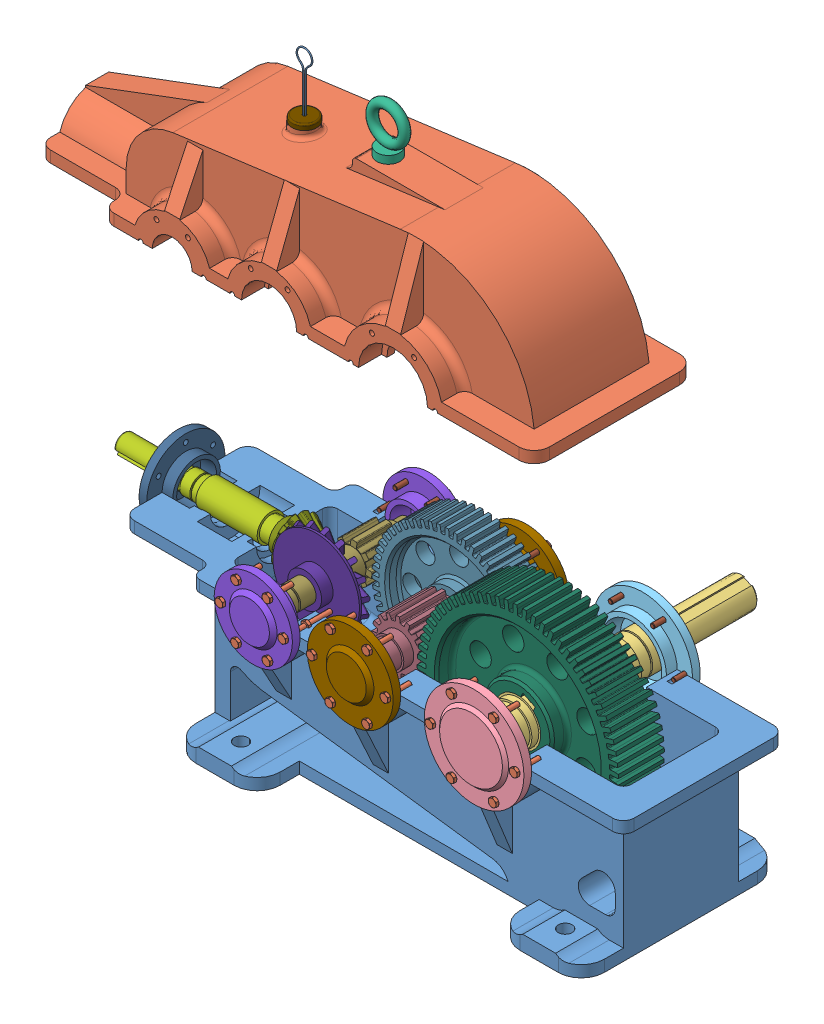
SolidWorks assembly Montagem redutor 4 eixos, configuration Valor predeterminado. Lengths in mm.
Overall size (757.14 825.89 416.81).
61 component instances, 20 part files, 122 mates.
Components (placement in the parent):
- corpo inferior-1: corpo inferior [Valor predeterminado] at (-28.8021 103.2767 0) size (676 185 260)
- corpo superior-1: corpo superior [Valor predeterminado] at (-68.7916 522.3028 75.8076) size (675.27 156.38 210)
- Peça 34-1: Peça 34 [Valor predeterminado] at (125.2979 103.2767 -709.2316) x (0 0 -1) z (0.906664 -0.421854 0) size (325 65 65)
- Peça 44-1: Peça 44 [Valor predeterminado] at (125.2979 103.2767 115) x (1 0 0) z (0 1 0) size (130 28 130)
- Peça 36-1: Peça 36 [Valor predeterminado] at (125.2979 103.2767 -115) x (1 0 0) z (0 -1 0) size (130 28 130)
- peça 3 - anilha-1: peça 3 - anilha [Valor predeterminado] at (-25.7916 713.0575 75.8076) size (54 83 30)
- Peça 19-1: Peça 19 [Valor predeterminado] at (-320.1919 103.2767 0) x (1 0 0) z (0 -0.917943 -0.396712) size (239.28 36 36)
- Peça 25-1: Peça 25 [Valor predeterminado] at (-162.8021 103.2767 -115) x (1 0 0) z (0 -1 0) size (102 32 102)
- Peça 29-1: Peça 29 [Valor predeterminado] at (-36.4021 103.2767 -115) x (1 0 0) z (0 -1 0) size (112 28 112)
- Peça 25-2: Peça 25 [Valor predeterminado] at (-162.8021 103.2767 115) x (1 0 0) z (0 1 0) size (102 32 102)
- Peça 29-2: Peça 29 [Valor predeterminado] at (-36.4021 103.2767 115) x (1 0 0) z (0 1 0) size (112 28 112)
- Peça 14-1: Peça 14 [Valor predeterminado] at (-375.8021 103.2767 0) x (0 -1 0) z (0 0 1) size (102 29 102)
- hex bolt gradeb_iso-2: hex bolt gradeb_iso [ISO 4015 - M6 x 25 x 18-N] at (-183.3016 67.7688 -119) x (0 0 1) z (-1 0 0) size (29 11.55 10)
- hex bolt gradeb_iso-3: hex bolt gradeb_iso [ISO 4015 - M6 x 25 x 18-N] at (-203.8021 103.2767 -119) x (0 0 1) z (-1 0 0) size (29 11.55 10)
- hex bolt gradeb_iso-6: hex bolt gradeb_iso [ISO 4015 - M6 x 25 x 18-N] at (-142.3006 138.7846 -119) x (0 0 1) z (-1 0 0) size (29 11.55 10)
- hex bolt gradeb_iso-7: hex bolt gradeb_iso [ISO 4015 - M6 x 25 x 18-N] at (-183.3016 138.7846 -119) x (0 0 1) z (-1 0 0) size (29 11.55 10)
- hex bolt gradeb_iso-8: hex bolt gradeb_iso [ISO 4015 - M6 x 25 x 18-N] at (-60.4016 144.8468 -119) x (0 0 1) z (-1 0 0) size (29 11.55 10)
- hex bolt gradeb_iso-9: hex bolt gradeb_iso [ISO 4015 - M6 x 25 x 18-N] at (-84.4021 103.2767 -119) x (0 0 1) z (-1 0 0) size (29 11.55 10)
- hex bolt gradeb_iso-10: hex bolt gradeb_iso [ISO 4015 - M6 x 25 x 18-N] at (-60.4016 61.7066 -119) x (0 0 1) z (-1 0 0) size (29 11.55 10)
- hex bolt gradeb_iso-11: hex bolt gradeb_iso [ISO 4015 - M6 x 25 x 18-N] at (-12.4006 61.7066 -119) x (0 0 1) z (-1 0 0) size (29 11.55 10)
- hex bolt gradeb_iso-12: hex bolt gradeb_iso [ISO 4015 - M6 x 25 x 18-N] at (11.5999 103.2767 -119) x (0 0 1) z (-1 0 0) size (29 11.55 10)
- hex bolt gradeb_iso-13: hex bolt gradeb_iso [ISO 4015 - M6 x 25 x 18-N] at (-12.4006 144.8468 -119) x (0 0 1) z (-1 0 0) size (29 11.55 10)
- hex bolt gradeb_iso-14: hex bolt gradeb_iso [ISO 4015 - M6 x 25 x 18-N] at (70.2979 103.2767 -119) x (0 0 1) z (-1 0 0) size (29 11.55 10)
- hex bolt gradeb_iso-15: hex bolt gradeb_iso [ISO 4015 - M6 x 25 x 18-N] at (97.7984 150.909 -119) x (0 0 1) z (-1 0 0) size (29 11.55 10)
- hex bolt gradeb_iso-16: hex bolt gradeb_iso [ISO 4015 - M6 x 25 x 18-N] at (97.7984 55.6445 -119) x (0 0 1) z (-1 0 0) size (29 11.55 10)
- hex bolt gradeb_iso-17: hex bolt gradeb_iso [ISO 4015 - M6 x 25 x 18-N] at (125.2979 103.2767 -109) x (0 0 1) z (-1 0 0) size (29 11.55 10)
- hex bolt gradeb_iso-18: hex bolt gradeb_iso [ISO 4015 - M6 x 25 x 18-N] at (180.2999 103.2767 -119) x (0 0 1) z (-1 0 0) size (29 11.55 10)
- hex bolt gradeb_iso-19: hex bolt gradeb_iso [ISO 4015 - M6 x 25 x 18-N] at (125.2979 103.2767 -109) x (0 0 1) z (-1 0 0) size (29 11.55 10)
- hex bolt gradeb_iso-20: hex bolt gradeb_iso [ISO 4015 - M6 x 25 x 18-N] at (152.7994 55.6445 -119) x (0 0 1) z (-1 0 0) size (29 11.55 10)
- hex bolt gradeb_iso-21: hex bolt gradeb_iso [ISO 4015 - M6 x 25 x 18-N] at (152.7994 150.909 -119) x (0 0 1) z (-1 0 0) size (29 11.55 10)
- hex bolt gradeb_iso-22: hex bolt gradeb_iso [ISO 4015 - M6 x 25 x 18-N] at (-121.8001 103.2767 -119) x (0 0 1) z (-1 0 0) size (29 11.55 10)
- hex bolt gradeb_iso-23: hex bolt gradeb_iso [ISO 4015 - M6 x 25 x 18-N] at (-142.3006 67.7688 -119) x (0 0 1) z (-1 0 0) size (29 11.55 10)
- Peça 24-1: Peça 24 [Valor predeterminado] at (-162.8021 103.2767 -27.9422) x (0 0 -1) z (0.995789 -0.091673 0) size (172 51.48 51.48)
- Peça 28-1: Peça 28 [Valor predeterminado] at (-36.4021 103.2767 -80.4292) x (0 0 -1) z (-0.999605 -0.028103 0) size (189 69.85 69.85)
- Peça 26-1: Peça 26 [Valor predeterminado] at (-36.4021 103.2767 -36.5) x (-0.999605 -0.028103 0) z (0 0 1) size (200.95 200.95 45)
- Peça 42-1: Peça 42 [Valor predeterminado] at (125.2979 103.2767 28) x (-0.906664 0.421854 0) z (0 0 1) size (262.46 262.46 60)
- Peça 21-1: Peça 21 [Valor predeterminado] at (-163.1706 103.2767 0) x (1 0 0) z (0 -0.917943 -0.396712) size (38.86 64.44 64.44)
- Peça 22-1: Peça 22 [Valor predeterminado] at (-162.8021 103.2767 20.6607) x (0 0 -1) z (0.719152 -0.694853 0) size (43 117.86 116.57)
- vareta de oleo-3: vareta de oleo [Valor predeterminado] at (-137.3021 649.47 75.8076) x (0 -1 0) z (0 0 1) size (295.59 32 32)
  - Peça 2-1: Peça 2 [Valor predeterminado] at (28.8886 2.1661 0) size (27 32 32)
  - Peça 1 - vareta do oleo-1: Peça 1 - vareta do oleo [Valor predeterminado] at (-84 2.1661 0) size (295.59 21.4 1.4)
- hex bolt gradeab_iso-1: hex bolt gradeab_iso [ISO 4014 - M6 x 30 x 18-N] at (125.2979 103.2767 119) x (0 0 -1) z (1 0 0) size (34 11.55 10)
- hex bolt gradeab_iso-2: hex bolt gradeab_iso [ISO 4014 - M6 x 30 x 18-N] at (-142.3006 138.7846 119) x (0 0 -1) z (1 0 0) size (34 11.55 10)
- hex bolt gradeab_iso-3: hex bolt gradeab_iso [ISO 4014 - M6 x 30 x 18-N] at (-183.3016 138.7846 119) x (0 0 -1) z (1 0 0) size (34 11.55 10)
- hex bolt gradeab_iso-5: hex bolt gradeab_iso [ISO 4014 - M6 x 30 x 18-N] at (-183.3016 67.7688 119) x (0 0 -1) z (1 0 0) size (34 11.55 10)
- hex bolt gradeab_iso-6: hex bolt gradeab_iso [ISO 4014 - M6 x 30 x 18-N] at (-142.3006 67.7688 119) x (0 0 -1) z (1 0 0) size (34 11.55 10)
- hex bolt gradeab_iso-7: hex bolt gradeab_iso [ISO 4014 - M6 x 30 x 18-N] at (-121.8021 103.2767 89) x (0 0 -1) z (1 0 0) size (34 11.55 10)
- hex bolt gradeab_iso-8: hex bolt gradeab_iso [ISO 4014 - M6 x 30 x 18-N] at (-121.8001 103.2767 119) x (0 0 -1) z (1 0 0) size (34 11.55 10)
- hex bolt gradeab_iso-9: hex bolt gradeab_iso [ISO 4014 - M6 x 30 x 18-N] at (-84.4021 103.2767 119) x (0 0 -1) z (1 0 0) size (34 11.55 10)
- hex bolt gradeab_iso-10: hex bolt gradeab_iso [ISO 4014 - M6 x 30 x 18-N] at (-60.4016 61.7066 119) x (0 0 -1) z (1 0 0) size (34 11.55 10)
- hex bolt gradeab_iso-11: hex bolt gradeab_iso [ISO 4014 - M6 x 30 x 18-N] at (-12.4006 61.7066 119) x (0 0 -1) z (1 0 0) size (34 11.55 10)
- hex bolt gradeab_iso-12: hex bolt gradeab_iso [ISO 4014 - M6 x 30 x 18-N] at (11.5999 103.2767 119) x (0 0 -1) z (1 0 0) size (34 11.55 10)
- hex bolt gradeab_iso-13: hex bolt gradeab_iso [ISO 4014 - M6 x 30 x 18-N] at (-12.4006 144.8468 119) x (0 0 -1) z (1 0 0) size (34 11.55 10)
- hex bolt gradeab_iso-14: hex bolt gradeab_iso [ISO 4014 - M6 x 30 x 18-N] at (-60.4016 144.8468 119) x (0 0 -1) z (1 0 0) size (34 11.55 10)
- hex bolt gradeab_iso-15: hex bolt gradeab_iso [ISO 4014 - M6 x 30 x 18-N] at (-203.8021 103.2767 119) x (0 0 -1) z (1 0 0) size (34 11.55 10)
- hex bolt gradeab_iso-16: hex bolt gradeab_iso [ISO 4014 - M6 x 30 x 18-N] at (70.2979 103.2767 119) x (0 0 -1) z (1 0 0) size (34 11.55 10)
- hex bolt gradeab_iso-17: hex bolt gradeab_iso [ISO 4014 - M6 x 30 x 18-N] at (97.7984 150.909 119) x (0 0 -1) z (1 0 0) size (34 11.55 10)
- hex bolt gradeab_iso-18: hex bolt gradeab_iso [ISO 4014 - M6 x 30 x 18-N] at (152.7994 150.909 119) x (0 0 -1) z (1 0 0) size (34 11.55 10)
- hex bolt gradeab_iso-19: hex bolt gradeab_iso [ISO 4014 - M6 x 30 x 18-N] at (180.2999 103.2767 119) x (0 0 -1) z (1 0 0) size (34 11.55 10)
- hex bolt gradeab_iso-20: hex bolt gradeab_iso [ISO 4014 - M6 x 30 x 18-N] at (152.7994 55.6445 119) x (0 0 -1) z (1 0 0) size (34 11.55 10)
- hex bolt gradeab_iso-21: hex bolt gradeab_iso [ISO 4014 - M6 x 30 x 18-N] at (97.7984 55.6445 119) x (0 0 -1) z (1 0 0) size (34 11.55 10)
Mates (geometry in assembly coordinates):
- Concêntrico1: concentric aligned: cylinder of corpo inferior-1 through (125.2979 103.2767 -130.001) axis (0 0 1) radius 45; cylinder of corpo inferior-1 through (125.2979 103.2767 75) axis (0 0 1) radius 45
- Concêntrico2: concentric anti-aligned: cylinder of corpo inferior-1 through (-365.8021 103.2767 0) axis (-1 0 0) radius 31; cylinder of corpo inferior-1 through (-229.8021 103.2767 0) axis (1 0 0) radius 31
- Concêntrico3: concentric aligned: cylinder of corpo inferior-1 through (125.2979 103.2767 -130.001) axis (0 0 1) radius 45; cylinder of Peça 34-1 through (125.2979 103.2767 -658.78) axis (0 0 1) radius 30
- Concêntrico4: concentric anti-aligned: cylinder of corpo inferior-1 through (125.2979 103.2767 -130.001) axis (0 0 1) radius 45; cylinder of Peça 44-1 through (125.2979 103.2767 31.1749) axis (0 0 -1) radius 45
- Coincidente1: coincident anti-aligned: plane of corpo inferior-1 through (-162.8021 103.2767 105) normal (0 0 1); plane of Peça 44-1 through (60.2979 103.2767 105) normal (0 0 -1)
- Concêntrico5: concentric anti-aligned: cylinder of Peça 34-1 through (125.2979 103.2767 -658.78) axis (0 0 1) radius 22.5; cone of Peça 36-1 through (125.2979 103.2767 -110) axis (0 0 -1)
- Concêntrico6: concentric aligned: cylinder of corpo inferior-1 through (125.2979 103.2767 -130.001) axis (0 0 1) radius 45; cylinder of Peça 36-1 through (125.2979 103.2767 -31.1749) axis (0 0 1) radius 45
- Coincidente2: coincident anti-aligned: plane of corpo inferior-1 through (-162.8021 103.2767 -105) normal (0 0 -1); plane of Peça 36-1 through (60.2979 103.2767 -105) normal (0 0 1)
- Distância1: distance = 2 mm anti-aligned: plane of Peça 34-1 through (135.8442 125.9433 67) normal (0 0 1); plane of corpo inferior-1 through (-182.8021 58.2767 65) normal (0 0 -1)
- Coincidente6: coincident anti-aligned: plane of corpo superior-1 through (73.1477 677.0575 100.8076) normal (0 1 0); plane of peça 3 - anilha-1 through (-25.7916 677.0575 75.8076) normal (0 -1 0)
- Concêntrico10: concentric aligned: cylinder of corpo superior-1 through (-25.7916 522.3028 75.8076) axis (0 1 0) radius 6.25; cylinder of peça 3 - anilha-1 through (-25.7916 657.0575 75.8076) axis (0 1 0) radius 6
- Concêntrico11: concentric aligned: cylinder of corpo inferior-1 through (-365.8021 103.2767 0) axis (-1 0 0) radius 31; cylinder of Peça 19-1 through (-474.027 103.2767 0) axis (-1 0 0) radius 18
- Coincidente8: coincident aligned: plane of corpo inferior-1 through (-254.8021 103.2767 -24) normal (1 0 0); plane of Peça 19-1 through (-254.8021 96.1359 16.523) normal (1 0 0)
- Coincidente10: coincident anti-aligned: plane of corpo inferior-1 through (-162.8021 103.2767 105) normal (0 0 1); plane of Peça 25-2 through (-213.8021 103.2767 105) normal (0 0 -1)
- Concêntrico13: concentric aligned: cylinder of corpo inferior-1 through (-162.8021 103.2767 -130.001) axis (0 0 1) radius 31; cylinder of Peça 25-1 through (-162.8021 103.2767 -31.1749) axis (0 0 1) radius 31
- Coincidente11: coincident anti-aligned: plane of corpo inferior-1 through (-162.8021 103.2767 -105) normal (0 0 -1); plane of Peça 25-1 through (-213.8021 103.2767 -105) normal (0 0 1)
- Concêntrico14: concentric anti-aligned: cylinder of corpo inferior-1 through (-36.4021 103.2767 -130.001) axis (0 0 1) radius 36; cylinder of Peça 29-2 through (-36.4021 103.2767 31.1749) axis (0 0 -1) radius 36
- Coincidente12: coincident anti-aligned: plane of corpo inferior-1 through (-162.8021 103.2767 105) normal (0 0 1); plane of Peça 29-2 through (-92.4021 103.2767 105) normal (0 0 -1)
- Concêntrico15: concentric aligned: cylinder of corpo inferior-1 through (-36.4021 103.2767 -130.001) axis (0 0 1) radius 36; cylinder of Peça 29-1 through (-36.4021 103.2767 -31.1749) axis (0 0 1) radius 36
- Coincidente13: coincident anti-aligned: plane of corpo inferior-1 through (-162.8021 103.2767 -105) normal (0 0 -1); plane of Peça 29-1 through (-92.4021 103.2767 -105) normal (0 0 1)
- Concêntrico16: concentric anti-aligned: cylinder of corpo inferior-1 through (-365.8021 103.2767 0) axis (-1 0 0) radius 31; cylinder of Peça 14-1 through (-291.9771 103.2767 0) axis (1 0 0) radius 31
- Coincidente14: coincident anti-aligned: plane of corpo inferior-1 through (-365.8021 103.2767 0) normal (-1 0 0); plane of Peça 14-1 through (-365.8021 154.2767 0) normal (1 0 0)
- Concêntrico171: concentric anti-aligned: cylinder of Peça 25-1 through (-183.3016 67.7688 -120) axis (0 0 1) radius 3.175; cylinder of hex bolt gradeb_iso-2 through (-183.3016 67.7688 -119) axis (0 0 -1) radius 3
- Coincidente151: coincident anti-aligned: plane of Peça 25-1 through (-213.8021 103.2767 -115) normal (0 0 -1); plane of hex bolt gradeb_iso-2 through (-183.3016 73.5423 -115) normal (0 0 1)
- Concêntrico18: concentric anti-aligned: cylinder of Peça 25-1 through (-203.8021 103.2767 -120) axis (0 0 1) radius 3.175; cylinder of hex bolt gradeb_iso-3 through (-203.8021 103.2767 -119) axis (0 0 -1) radius 3
- Coincidente16: coincident anti-aligned: plane of Peça 25-1 through (-213.8021 103.2767 -115) normal (0 0 -1); plane of hex bolt gradeb_iso-3 through (-203.8021 109.0502 -115) normal (0 0 1)
- Concêntrico21: concentric anti-aligned: cylinder of Peça 25-1 through (-142.3006 138.7846 -120) axis (0 0 1) radius 3.175; cylinder of hex bolt gradeb_iso-6 through (-142.3006 138.7846 -119) axis (0 0 -1) radius 3
- Coincidente17: coincident anti-aligned: plane of Peça 25-1 through (-213.8021 103.2767 -115) normal (0 0 -1); plane of hex bolt gradeb_iso-6 through (-142.3006 144.5581 -115) normal (0 0 1)
- Concêntrico22: concentric anti-aligned: cylinder of Peça 25-1 through (-183.3016 138.7846 -120) axis (0 0 1) radius 3.175; cylinder of hex bolt gradeb_iso-7 through (-183.3016 138.7846 -119) axis (0 0 -1) radius 3
- Coincidente18: coincident anti-aligned: plane of Peça 25-1 through (-213.8021 103.2767 -115) normal (0 0 -1); plane of hex bolt gradeb_iso-7 through (-183.3016 144.5581 -115) normal (0 0 1)
- Concêntrico23: concentric anti-aligned: cylinder of Peça 29-1 through (-60.4016 144.8468 -120) axis (0 0 1) radius 3.175; cylinder of hex bolt gradeb_iso-8 through (-60.4016 144.8468 -119) axis (0 0 -1) radius 3
- Coincidente19: coincident anti-aligned: plane of Peça 29-1 through (-92.4021 103.2767 -115) normal (0 0 -1); plane of hex bolt gradeb_iso-8 through (-60.4016 150.6203 -115) normal (0 0 1)
- Concêntrico24: concentric anti-aligned: cylinder of Peça 29-1 through (-84.4021 103.2767 -120) axis (0 0 1) radius 3.175; cylinder of hex bolt gradeb_iso-9 through (-84.4021 103.2767 -119) axis (0 0 -1) radius 3
- Coincidente20: coincident anti-aligned: plane of Peça 29-1 through (-92.4021 103.2767 -115) normal (0 0 -1); plane of hex bolt gradeb_iso-9 through (-84.4021 109.0502 -115) normal (0 0 1)
- Concêntrico25: concentric anti-aligned: cylinder of Peça 29-1 through (-60.4016 61.7066 -120) axis (0 0 1) radius 3.175; cylinder of hex bolt gradeb_iso-10 through (-60.4016 61.7066 -119) axis (0 0 -1) radius 3
- Coincidente21: coincident anti-aligned: plane of Peça 29-1 through (-92.4021 103.2767 -115) normal (0 0 -1); plane of hex bolt gradeb_iso-10 through (-60.4016 67.4802 -115) normal (0 0 1)
- Concêntrico26: concentric anti-aligned: cylinder of Peça 29-1 through (-12.4006 61.7066 -120) axis (0 0 1) radius 3.175; cylinder of hex bolt gradeb_iso-11 through (-12.4006 61.7066 -119) axis (0 0 -1) radius 3
- Coincidente22: coincident anti-aligned: plane of Peça 29-1 through (-92.4021 103.2767 -115) normal (0 0 -1); plane of hex bolt gradeb_iso-11 through (-12.4006 67.4802 -115) normal (0 0 1)
- Concêntrico27: concentric anti-aligned: cylinder of Peça 29-1 through (11.5999 103.2767 -120) axis (0 0 1) radius 3.175; cylinder of hex bolt gradeb_iso-12 through (11.5999 103.2767 -119) axis (0 0 -1) radius 3
- Coincidente23: coincident anti-aligned: plane of Peça 29-1 through (-92.4021 103.2767 -115) normal (0 0 -1); plane of hex bolt gradeb_iso-12 through (11.5999 109.0502 -115) normal (0 0 1)
- Concêntrico28: concentric anti-aligned: cylinder of Peça 29-1 through (-12.4006 144.8468 -120) axis (0 0 1) radius 3.175; cylinder of hex bolt gradeb_iso-13 through (-12.4006 144.8468 -119) axis (0 0 -1) radius 3
- Coincidente24: coincident anti-aligned: plane of Peça 29-1 through (-92.4021 103.2767 -115) normal (0 0 -1); plane of hex bolt gradeb_iso-13 through (-12.4006 150.6203 -115) normal (0 0 1)
- Concêntrico29: concentric anti-aligned: cylinder of Peça 36-1 through (70.2979 103.2767 -119) axis (0 0 1) radius 3.175; cylinder of hex bolt gradeb_iso-14 through (70.2979 103.2767 -119) axis (0 0 -1) radius 3
- Coincidente25: coincident anti-aligned: plane of Peça 36-1 through (60.2979 103.2767 -115) normal (0 0 -1); plane of hex bolt gradeb_iso-14 through (70.2979 109.0502 -115) normal (0 0 1)
- Concêntrico30: concentric anti-aligned: cylinder of Peça 36-1 through (97.7984 150.909 -119) axis (0 0 1) radius 3.175; cylinder of hex bolt gradeb_iso-15 through (97.7984 150.909 -119) axis (0 0 -1) radius 3
- Coincidente26: coincident anti-aligned: plane of Peça 36-1 through (60.2979 103.2767 -115) normal (0 0 -1); plane of hex bolt gradeb_iso-15 through (97.7984 156.6825 -115) normal (0 0 1)
- Concêntrico31: concentric anti-aligned: cylinder of Peça 36-1 through (97.7984 55.6445 -119) axis (0 0 1) radius 3.175; cylinder of hex bolt gradeb_iso-16 through (97.7984 55.6445 -119) axis (0 0 -1) radius 3
- Coincidente27: coincident anti-aligned: plane of Peça 36-1 through (60.2979 103.2767 -115) normal (0 0 -1); plane of hex bolt gradeb_iso-16 through (97.7984 61.418 -115) normal (0 0 1)
- Concêntrico321: concentric aligned: cylinder of corpo inferior-1 through (125.2979 103.2767 105) axis (0 0 -1) radius 65; cylinder of hex bolt gradeb_iso-17 through (125.2979 103.2767 -109) axis (0 0 -1) radius 3
- Coincidente281: coincident anti-aligned: plane of corpo inferior-1 through (-162.8021 103.2767 -105) normal (0 0 -1); plane of hex bolt gradeb_iso-17 through (125.2979 109.0502 -105) normal (0 0 1)
- Concêntrico33: concentric anti-aligned: cylinder of Peça 36-1 through (180.2999 103.2767 -119) axis (0 0 1) radius 3.175; cylinder of hex bolt gradeb_iso-18 through (180.2999 103.2767 -119) axis (0 0 -1) radius 3
- Coincidente29: coincident anti-aligned: plane of Peça 36-1 through (60.2979 103.2767 -115) normal (0 0 -1); plane of hex bolt gradeb_iso-18 through (180.2999 109.0502 -115) normal (0 0 1)
- Concêntrico341: concentric anti-aligned: cylinder of corpo inferior-1 through (125.2979 103.2767 -130.001) axis (0 0 1) radius 45; cylinder of hex bolt gradeb_iso-19 through (125.2979 103.2767 -109) axis (0 0 -1) radius 3
- Coincidente301: coincident anti-aligned: plane of corpo inferior-1 through (-162.8021 103.2767 -105) normal (0 0 -1); plane of hex bolt gradeb_iso-19 through (125.2979 109.0502 -105) normal (0 0 1)
- Concêntrico35: concentric anti-aligned: cylinder of Peça 36-1 through (152.7994 55.6445 -119) axis (0 0 1) radius 3.175; cylinder of hex bolt gradeb_iso-20 through (152.7994 55.6445 -119) axis (0 0 -1) radius 3
- Coincidente31: coincident anti-aligned: plane of Peça 36-1 through (60.2979 103.2767 -115) normal (0 0 -1); plane of hex bolt gradeb_iso-20 through (152.7994 61.418 -115) normal (0 0 1)
- Concêntrico36: concentric anti-aligned: cylinder of Peça 36-1 through (152.7994 150.909 -119) axis (0 0 1) radius 3.175; cylinder of hex bolt gradeb_iso-21 through (152.7994 150.909 -119) axis (0 0 -1) radius 3
- Coincidente32: coincident anti-aligned: plane of Peça 36-1 through (60.2979 103.2767 -115) normal (0 0 -1); plane of hex bolt gradeb_iso-21 through (152.7994 156.6825 -115) normal (0 0 1)
- Concêntrico37: concentric anti-aligned: cylinder of Peça 25-1 through (-121.8001 103.2767 -120) axis (0 0 1) radius 3.175; cylinder of hex bolt gradeb_iso-22 through (-121.8001 103.2767 -119) axis (0 0 -1) radius 3
- Coincidente33: coincident anti-aligned: plane of Peça 25-1 through (-213.8021 103.2767 -115) normal (0 0 -1); plane of hex bolt gradeb_iso-22 through (-121.8001 109.0502 -115) normal (0 0 1)
- Concêntrico38: concentric anti-aligned: cylinder of Peça 25-1 through (-142.3006 67.7688 -120) axis (0 0 1) radius 3.175; cylinder of hex bolt gradeb_iso-23 through (-142.3006 67.7688 -119) axis (0 0 -1) radius 3
- Coincidente34: coincident anti-aligned: plane of Peça 25-1 through (-213.8021 103.2767 -115) normal (0 0 -1); plane of hex bolt gradeb_iso-23 through (-142.3006 73.5423 -115) normal (0 0 1)
- Concêntrico342: concentric anti-aligned: cylinder of Peça 34-1 through (125.2979 103.2767 -658.78) axis (0 0 1) radius 30; cylinder of Peça 42-1 through (125.2979 103.2767 58) axis (0 0 -1) radius 30
- Coincidente303: coincident aligned: plane of Peça 34-1 through (127.2624 128.8334 6.5) normal (0.906664 -0.421854 0); plane of Peça 42-1 through (131.9028 138.8067 -2) normal (0.906664 -0.421854 0)
- Coincidente304: coincident aligned: plane of Peça 34-1 through (136.8988 128.21 58) normal (0 0 1); plane of Peça 42-1 through (125.2979 103.2767 58) normal (0 0 1)
- Concêntrico343: concentric aligned: cylinder of corpo inferior-1 through (-36.4021 103.2767 -130.001) axis (0 0 1) radius 36; cylinder of Peça 28-1 through (-36.4021 103.2767 105.5535) axis (0 0 1) radius 22.5
- Coincidente305: coincident anti-aligned: plane of corpo inferior-1 through (-182.8021 58.2767 65) normal (0 0 -1); plane of Peça 28-1 through (-35.9103 85.7836 65) normal (0 0 1)
- Concêntrico344: concentric anti-aligned: cylinder of Peça 28-1 through (-36.4021 103.2767 105.5535) axis (0 0 1) radius 22.5; cylinder of Peça 26-1 through (-36.4021 103.2767 -14) axis (0 0 -1) radius 22.5
- Paralelo1: parallel aligned: plane of Peça 28-1 through (-28.9131 85.9804 -52) normal (-0.999605 -0.028103 0); plane of Peça 26-1 through (-28.309 82.2827 -14) normal (-0.999605 -0.028103 0)
- Coincidente308: coincident anti-aligned: plane of Peça 28-1 through (-35.6996 78.2866 -14) normal (0 0 -1); plane of Peça 26-1 through (-36.4021 103.2767 -14) normal (0 0 1)
- Posic. engrenagem1: gear = 35 : 55 mm: cylinder of Peça 34-1 through (125.2979 103.2767 -658.78) axis (0 0 1) radius 27.5; cylinder of Peça 28-1 through (-36.4021 103.2767 105.5535) axis (0 0 1) radius 17.5
- Concêntrico345: concentric aligned: cylinder of corpo inferior-1 through (-162.8021 103.2767 -130.001) axis (0 0 1) radius 31; cylinder of Peça 24-1 through (-162.8021 103.2767 154.7526) axis (0 0 1) radius 15
- Distância2: distance = 6 mm anti-aligned: plane of corpo inferior-1 through (-182.8021 58.2767 -65) normal (0 0 1); plane of Peça 24-1 through (-161.1979 120.703 -71) normal (0 0 -1)
- Posic. engrenagem2: gear = 30 : 35 mm: cylinder of Peça 28-1 through (-36.4021 103.2767 105.5535) axis (0 0 1) radius 17.5; cylinder of Peça 24-1 through (-162.8021 103.2767 154.7526) axis (0 0 1) radius 15
- Concêntrico346: concentric aligned: cone of Peça 24-1 through (-162.8021 103.2767 5) axis (0 0 1); cone of Peça 22-1 through (-162.8021 103.2767 48) axis (0 0 1)
- Concêntrico347: concentric aligned: cylinder of Peça 19-1 through (-474.027 103.2767 0) axis (-1 0 0) radius 15; cylinder of Peça 21-1 through (-333.0795 103.2767 0) axis (-1 0 0) radius 14
- Coincidente309: coincident anti-aligned: circle of Peça 24-1; plane of Peça 22-1 through (-147.4122 119.2048 5) normal (0 0 -1)
- Posic. engrenagem3: gear = 36 : 36 mm: cylinder of Peça 24-1 through (-162.8021 103.2767 154.7526) axis (0 0 1) radius 18; cylinder of Peça 19-1 through (-474.027 103.2767 0) axis (-1 0 0) radius 18
- Paralelo2: parallel aligned: plane of Peça 19-1 through (-207.8021 103.3781 9.8483) normal (0 -0.917943 -0.396712); plane of Peça 21-1 through (-198.9411 100.3779 11.7489) normal (0 -0.917943 -0.396712)
- Coincidente311: coincident anti-aligned: plane of Peça 19-1 through (-237.8021 97.3261 13.7691) normal (1 0 0); plane of Peça 21-1 through (-237.8021 107.1134 -8.8775) normal (-1 0 0)
- Concêntrico348: concentric aligned: cylinder of corpo superior-1 through (-135.136 522.3028 75.8076) axis (0 1 0) radius 8.25; cylinder of vareta de oleo-3/Peça 2-1 through (-135.136 689.6639 75.8076) axis (0 1 0) radius 8
- Coincidente312: coincident anti-aligned: plane of corpo superior-1 through (-135.7916 661.1104 75.8076) normal (0 1 0); plane of vareta de oleo-3/Peça 2-1 through (-119.136 661.1104 75.8076) normal (0 -1 0)
- Concêntrico3491: concentric anti-aligned: cylinder of Peça 44-1 through (125.2979 103.2767 31.1749) axis (0 0 -1) radius 65; cylinder of hex bolt gradeab_iso-1 through (125.2979 103.2767 119) axis (0 0 1) radius 3
- Coincidente3131: coincident anti-aligned: plane of Peça 44-1 through (60.2979 103.2767 115) normal (0 0 1); plane of hex bolt gradeab_iso-1 through (125.2979 109.0502 115) normal (0 0 -1)
- Concêntrico350: concentric anti-aligned: cylinder of Peça 25-2 through (-142.3006 138.7846 120) axis (0 0 -1) radius 3.175; cylinder of hex bolt gradeab_iso-2 through (-142.3006 138.7846 119) axis (0 0 1) radius 5
- Coincidente314: coincident anti-aligned: plane of Peça 25-2 through (-213.8021 103.2767 115) normal (0 0 1); plane of hex bolt gradeab_iso-2 through (-142.3006 144.5581 115) normal (0 0 -1)
- Concêntrico351: concentric anti-aligned: cylinder of Peça 25-2 through (-183.3016 138.7846 120) axis (0 0 -1) radius 3.175; cylinder of hex bolt gradeab_iso-3 through (-183.3016 138.7846 119) axis (0 0 1) radius 5
- Coincidente315: coincident anti-aligned: plane of Peça 25-2 through (-213.8021 103.2767 115) normal (0 0 1); plane of hex bolt gradeab_iso-3 through (-183.3016 144.5581 115) normal (0 0 -1)
- Concêntrico353: concentric anti-aligned: cylinder of Peça 25-2 through (-183.3016 67.7688 120) axis (0 0 -1) radius 3.175; cylinder of hex bolt gradeab_iso-5 through (-183.3016 67.7688 119) axis (0 0 1) radius 5
- Coincidente317: coincident anti-aligned: plane of Peça 25-2 through (-213.8021 103.2767 115) normal (0 0 1); plane of hex bolt gradeab_iso-5 through (-183.3016 73.5423 115) normal (0 0 -1)
- Concêntrico354: concentric anti-aligned: cylinder of Peça 25-2 through (-142.3006 67.7688 120) axis (0 0 -1) radius 3.175; cylinder of hex bolt gradeab_iso-6 through (-142.3006 67.7688 119) axis (0 0 1) radius 5
- Coincidente318: coincident anti-aligned: plane of Peça 25-2 through (-213.8021 103.2767 115) normal (0 0 1); plane of hex bolt gradeab_iso-6 through (-142.3006 73.5423 115) normal (0 0 -1)
- Concêntrico3551: concentric aligned: cylinder of corpo inferior-1 through (-121.8021 103.2767 85) axis (0 0 1) radius 3.175; cylinder of hex bolt gradeab_iso-7 through (-121.8021 103.2767 89) axis (0 0 1) radius 5
- Coincidente3191: coincident anti-aligned: plane of corpo inferior-1 through (-121.8021 103.2767 85) normal (0 0 1); plane of hex bolt gradeab_iso-7 through (-121.8021 109.0502 85) normal (0 0 -1)
- Concêntrico356: concentric anti-aligned: cylinder of Peça 25-2 through (-121.8001 103.2767 120) axis (0 0 -1) radius 3.175; cylinder of hex bolt gradeab_iso-8 through (-121.8001 103.2767 119) axis (0 0 1) radius 5
- Coincidente320: coincident anti-aligned: plane of Peça 25-2 through (-213.8021 103.2767 115) normal (0 0 1); plane of hex bolt gradeab_iso-8 through (-121.8001 109.0502 115) normal (0 0 -1)
- Concêntrico357: concentric anti-aligned: cylinder of Peça 29-2 through (-84.4021 103.2767 120) axis (0 0 -1) radius 3.175; cylinder of hex bolt gradeab_iso-9 through (-84.4021 103.2767 119) axis (0 0 1) radius 5
- Coincidente321: coincident anti-aligned: plane of Peça 29-2 through (-92.4021 103.2767 115) normal (0 0 1); plane of hex bolt gradeab_iso-9 through (-84.4021 109.0502 115) normal (0 0 -1)
- Concêntrico358: concentric anti-aligned: cylinder of Peça 29-2 through (-60.4016 61.7066 120) axis (0 0 -1) radius 3.175; cylinder of hex bolt gradeab_iso-10 through (-60.4016 61.7066 119) axis (0 0 1) radius 5
- Coincidente322: coincident anti-aligned: plane of Peça 29-2 through (-92.4021 103.2767 115) normal (0 0 1); plane of hex bolt gradeab_iso-10 through (-60.4016 67.4802 115) normal (0 0 -1)
- Concêntrico359: concentric anti-aligned: cylinder of Peça 29-2 through (-12.4006 61.7066 120) axis (0 0 -1) radius 3.175; cylinder of hex bolt gradeab_iso-11 through (-12.4006 61.7066 119) axis (0 0 1) radius 5
- Coincidente323: coincident anti-aligned: plane of Peça 29-2 through (-92.4021 103.2767 115) normal (0 0 1); plane of hex bolt gradeab_iso-11 through (-12.4006 67.4802 115) normal (0 0 -1)
- Concêntrico360: concentric anti-aligned: cylinder of Peça 29-2 through (11.5999 103.2767 120) axis (0 0 -1) radius 3.175; cylinder of hex bolt gradeab_iso-12 through (11.5999 103.2767 119) axis (0 0 1) radius 5
- Coincidente324: coincident anti-aligned: plane of Peça 29-2 through (-92.4021 103.2767 115) normal (0 0 1); plane of hex bolt gradeab_iso-12 through (11.5999 109.0502 115) normal (0 0 -1)
- Concêntrico361: concentric anti-aligned: cylinder of Peça 29-2 through (-12.4006 144.8468 120) axis (0 0 -1) radius 3.175; cylinder of hex bolt gradeab_iso-13 through (-12.4006 144.8468 119) axis (0 0 1) radius 5
- Coincidente325: coincident anti-aligned: plane of Peça 29-2 through (-92.4021 103.2767 115) normal (0 0 1); plane of hex bolt gradeab_iso-13 through (-12.4006 150.6203 115) normal (0 0 -1)
- Concêntrico362: concentric anti-aligned: cylinder of Peça 29-2 through (-60.4016 144.8468 120) axis (0 0 -1) radius 3.175; cylinder of hex bolt gradeab_iso-14 through (-60.4016 144.8468 119) axis (0 0 1) radius 5
- Coincidente326: coincident anti-aligned: plane of Peça 29-2 through (-92.4021 103.2767 115) normal (0 0 1); plane of hex bolt gradeab_iso-14 through (-60.4016 150.6203 115) normal (0 0 -1)
- Concêntrico363: concentric anti-aligned: cylinder of Peça 25-2 through (-203.8021 103.2767 120) axis (0 0 -1) radius 3.175; cylinder of hex bolt gradeab_iso-15 through (-203.8021 103.2767 119) axis (0 0 1) radius 5
- Coincidente327: coincident anti-aligned: plane of Peça 25-2 through (-213.8021 103.2767 115) normal (0 0 1); plane of hex bolt gradeab_iso-15 through (-203.8021 109.0502 115) normal (0 0 -1)
- Concêntrico364: concentric anti-aligned: cylinder of Peça 44-1 through (70.2979 103.2767 119) axis (0 0 -1) radius 3.175; cylinder of hex bolt gradeab_iso-16 through (70.2979 103.2767 119) axis (0 0 1) radius 5
- Coincidente328: coincident anti-aligned: plane of Peça 44-1 through (60.2979 103.2767 115) normal (0 0 1); plane of hex bolt gradeab_iso-16 through (70.2979 109.0502 115) normal (0 0 -1)
- Concêntrico365: concentric anti-aligned: cylinder of Peça 44-1 through (97.7984 150.909 119) axis (0 0 -1) radius 3.175; cylinder of hex bolt gradeab_iso-17 through (97.7984 150.909 119) axis (0 0 1) radius 5
- Coincidente329: coincident anti-aligned: plane of Peça 44-1 through (60.2979 103.2767 115) normal (0 0 1); plane of hex bolt gradeab_iso-17 through (97.7984 156.6825 115) normal (0 0 -1)
- Concêntrico366: concentric anti-aligned: cylinder of Peça 44-1 through (152.7994 150.909 119) axis (0 0 -1) radius 3.175; cylinder of hex bolt gradeab_iso-18 through (152.7994 150.909 119) axis (0 0 1) radius 5
- Coincidente330: coincident anti-aligned: plane of Peça 44-1 through (60.2979 103.2767 115) normal (0 0 1); plane of hex bolt gradeab_iso-18 through (152.7994 156.6825 115) normal (0 0 -1)
- Concêntrico367: concentric anti-aligned: cylinder of Peça 44-1 through (180.2999 103.2767 119) axis (0 0 -1) radius 3.175; cylinder of hex bolt gradeab_iso-19 through (180.2999 103.2767 119) axis (0 0 1) radius 5
- Coincidente331: coincident anti-aligned: plane of Peça 44-1 through (60.2979 103.2767 115) normal (0 0 1); plane of hex bolt gradeab_iso-19 through (180.2999 109.0502 115) normal (0 0 -1)
- Concêntrico368: concentric anti-aligned: cylinder of Peça 44-1 through (152.7994 55.6445 119) axis (0 0 -1) radius 3.175; cylinder of hex bolt gradeab_iso-20 through (152.7994 55.6445 119) axis (0 0 1) radius 5
- Coincidente332: coincident anti-aligned: plane of Peça 44-1 through (60.2979 103.2767 115) normal (0 0 1); plane of hex bolt gradeab_iso-20 through (152.7994 61.418 115) normal (0 0 -1)
- Concêntrico369: concentric anti-aligned: cylinder of Peça 44-1 through (97.7984 55.6445 119) axis (0 0 -1) radius 3.175; cylinder of hex bolt gradeab_iso-21 through (97.7984 55.6445 119) axis (0 0 1) radius 5
- Coincidente333: coincident anti-aligned: plane of Peça 44-1 through (60.2979 103.2767 115) normal (0 0 1); plane of hex bolt gradeab_iso-21 through (97.7984 61.418 115) normal (0 0 -1)
